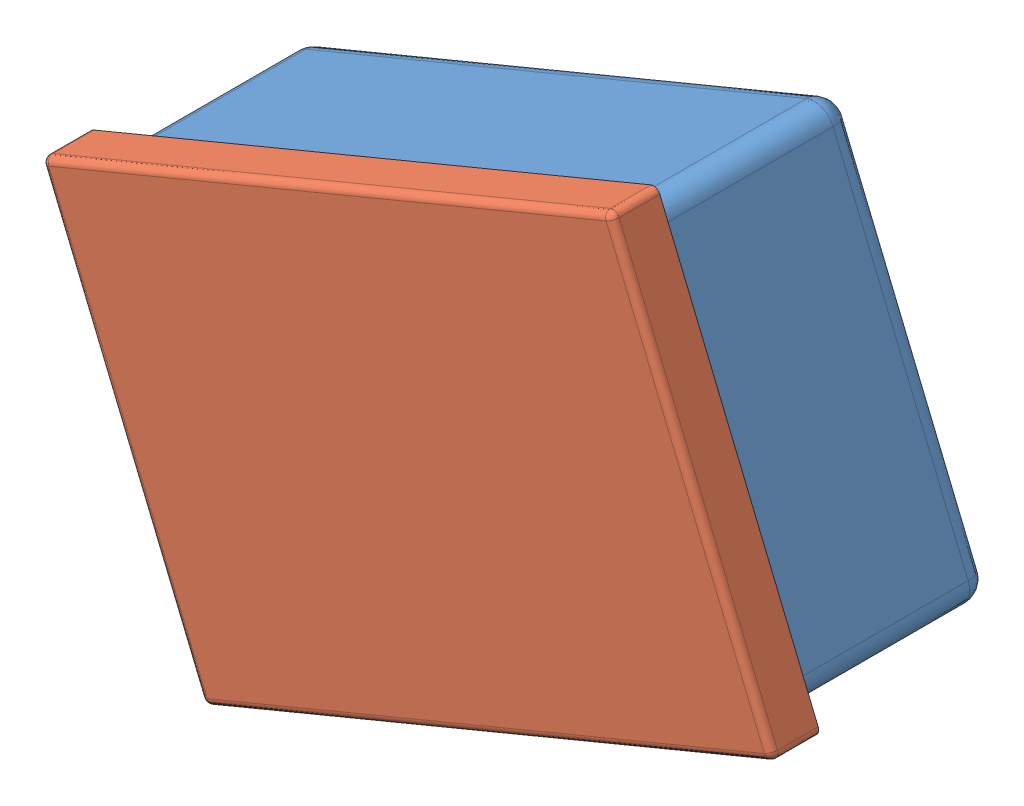
SolidWorks assembly Mont1, configuration Valor predeterminado. Lengths in mm.
Overall size (108.19 93.05 41.93).
2 component instances, 2 part files, 3 mates.
Components (placement in the parent):
- Bracelete_Bebe-1: Bracelete_Bebe [Valor predeterminado] at (-246.7495 62.5364 80.1653) x (0.383049 -0.923728 0) z (0 0 1) size (58 86 41.93)
- Tampa_Bracelete_Filho-2: Tampa_Bracelete_Filho [Valor predeterminado] at (-246.9793 74.8202 112.5476) x (-0.923728 -0.383049 0) z (0 0 -1) size (91 63 7)
Mates (geometry in assembly coordinates):
- Paralelo5: parallel anti-aligned: plane of Bracelete_Bebe-1 through (-246.7495 62.5364 80.1653) normal (0 0 1); plane of Tampa_Bracelete_Filho-2 through (-246.9793 74.8202 112.5476) normal (0 0 -1)
- Coincidente8: coincident anti-aligned: plane of Bracelete_Bebe-1 through (-211.1072 105.1747 117.1653) normal (0.923728 0.383049 0); plane of Tampa_Bracelete_Filho-2 through (-211.1072 105.1747 107.5476) normal (-0.923728 -0.383049 0)
- Coincidente9: coincident anti-aligned: plane of Bracelete_Bebe-1 through (-211.1072 105.1747 117.1653) normal (-0.383049 0.923728 0); plane of Tampa_Bracelete_Filho-2 through (-211.1072 105.1747 107.5476) normal (0.383049 -0.923728 0)
